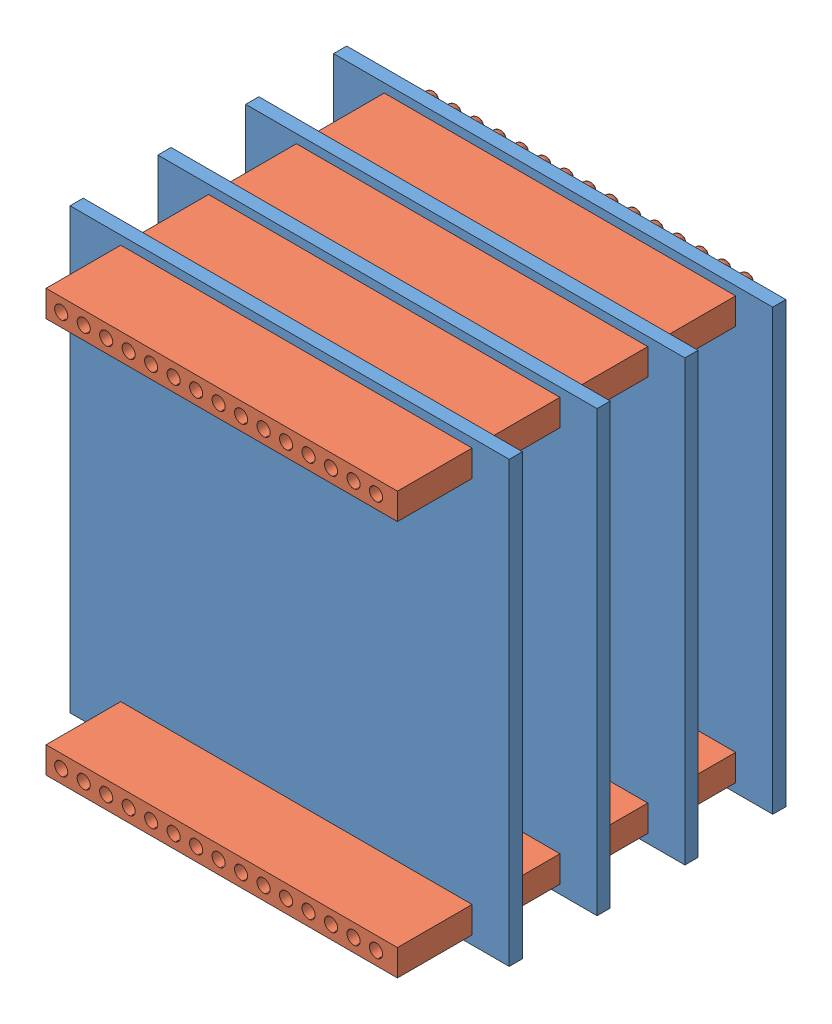
SolidWorks assembly electronics core internal, configuration Default. Lengths in mm.
Overall size (50 50 42.5).
15 component instances, 2 part files, 12 mates.
Components (placement in the parent):
- idv pcb with headers-1: idv pcb with headers [Default] at (-85.6849 11.1309 -28.0523) size (50 50 12.5)
  - psb-1: psb [Default] at (15.9558 27.0682 38.3955) size (50 50 1.5)
  - header pins short-1: header pins short [Default] at (-1.5442 49.5682 39.8955) x (1 0 0) z (0 0 -1) size (40 3 12.5)
  - header pins short-2: header pins short [Default] at (-1.5442 4.5682 39.8955) x (1 0 0) z (0 0 -1) size (40 3 12.5)
- idv pcb with headers-2: idv pcb with headers [Default] at (-85.6849 11.1309 -18.0523) size (50 50 12.5)
  - psb-1: psb [Default] at (15.9558 27.0682 38.3955) size (50 50 1.5)
  - header pins short-1: header pins short [Default] at (-1.5442 49.5682 39.8955) x (1 0 0) z (0 0 -1) size (40 3 12.5)
  - header pins short-2: header pins short [Default] at (-1.5442 4.5682 39.8955) x (1 0 0) z (0 0 -1) size (40 3 12.5)
- idv pcb with headers-3: idv pcb with headers [Default] at (-85.6849 11.1309 -8.0523) size (50 50 12.5)
  - psb-1: psb [Default] at (15.9558 27.0682 38.3955) size (50 50 1.5)
  - header pins short-1: header pins short [Default] at (-1.5442 49.5682 39.8955) x (1 0 0) z (0 0 -1) size (40 3 12.5)
  - header pins short-2: header pins short [Default] at (-1.5442 4.5682 39.8955) x (1 0 0) z (0 0 -1) size (40 3 12.5)
- psb-1: psb [Default] at (-69.7291 38.199 0.3432) size (50 50 1.5)
- header pins short-1: header pins short [Default] at (-87.2291 60.699 1.8432) x (1 0 0) z (0 0 -1) size (40 3 12.5)
- header pins short-2: header pins short [Default] at (-87.2291 15.699 1.8432) x (1 0 0) z (0 0 -1) size (40 3 12.5)
Mates (geometry in assembly coordinates):
- Coincident1: coincident anti-aligned: plane of idv pcb with headers-2/header pins short-2 through (-87.2291 15.699 30.3432) normal (0 0 1); plane of idv pcb with headers-3/psb-1 through (-69.7291 38.199 30.3432) normal (0 0 -1)
- Coincident2: coincident aligned: circle of idv pcb with headers-2/header pins short-2; cylinder of idv pcb with headers-3/header pins short-2 through (-51.3891 15.699 27.8432) axis (0 0 1) radius 0.75
- Coincident3: coincident anti-aligned: plane of idv pcb with headers-1/header pins short-2 through (-87.2291 15.699 20.3432) normal (0 0 1); plane of idv pcb with headers-2/psb-1 through (-69.7291 38.199 20.3432) normal (0 0 -1)
- Coincident4: coincident aligned: circle of idv pcb with headers-1/header pins short-2; cylinder of idv pcb with headers-2/header pins short-2 through (-51.3891 15.699 17.8432) axis (0 0 1) radius 0.75
- Concentric1: concentric aligned: cylinder of idv pcb with headers-2/header pins short-1 through (-87.2291 60.699 30.3432) axis (0 0 -1) radius 0.75; cylinder of idv pcb with headers-3/header pins short-1 through (-87.2291 60.699 40.3432) axis (0 0 -1) radius 0.75
- Coincident5: coincident aligned: cylinder of idv pcb with headers-1/header pins short-1 through (-87.2291 60.699 7.8432) axis (0 0 1) radius 0.75; circle of idv pcb with headers-3/header pins short-1
- Coincident6: coincident aligned: circle of psb-1; cylinder of header pins short-2 through (-51.3891 15.699 -2.1568) axis (0 0 1) radius 0.75
- Coincident7: coincident aligned: circle of psb-1; circle of header pins short-2
- Coincident8: coincident anti-aligned: circle of psb-1; circle of header pins short-1
- Coincident9: coincident aligned: circle of psb-1; cylinder of header pins short-1 through (-51.3891 60.699 -2.1568) axis (0 0 1) radius 0.75
- Concentric2: concentric aligned: circle of idv pcb with headers-1/psb-1; circle of header pins short-1
- Coincident10: coincident aligned: circle of idv pcb with headers-1/psb-1; circle of header pins short-2
